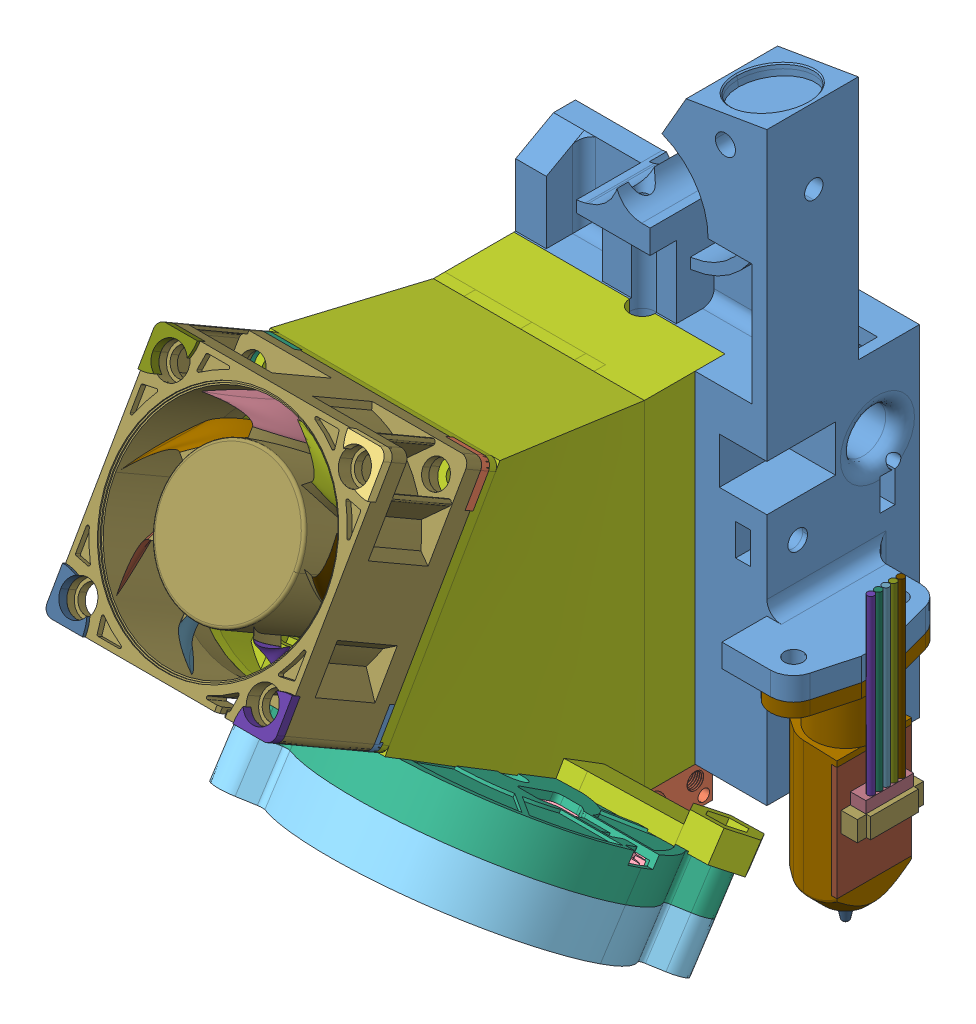
SolidWorks assembly orca-2-cygnus-e3d-extruder+bltouch, configuration Default. Lengths in mm.
Overall size (80.28 120.16 105.46).
52 component instances, 36 part files, 14 mates.
Components (placement in the parent):
- orca2_single_extruder_base-orca2 cyg isolated extruder-1: orca2_single_extruder_base-orca2 cyg isolated extruder [Default] at origin size (77.53 101.68 34.3)
- e3d_v6_175-1: e3d_v6_175 [Default] at (-15.9108 -245.9364 162.3902) x (0 0 1) z (0 1 0) size (28.15 25.09 61.3)
  - Heaterblock.stp-1: Heaterblock.stp [Default] at (45.073 9.7855 4.6892) size (20 16.05 11.6)
  - Heatsink.stp-1: Heatsink.stp [Default] at (11.1849 26.0506 18.2892) x (0.990938 -0.134318 0) z (0 0 1) size (22.3 22.3 42.75)
  - Nozzle 0.4mm.stp-1: Nozzle 0.4mm.stp [Default] at (26.1197 -35.9963 1.6892) x (0.866025 -0.5 0) z (0 0 1) size (8.08 7 12.54)
  - Heatbreak.stp-1: Heatbreak.stp [Default] at (4.469 -23.4963 11.1892) size (7.03 7.04 22.45)
- BLTouch-Smart V3.1-1: BLTouch-Smart V3.1 [BLTouch-Smart V3.1] at (-70.1572 -203.2472 166.8592) x (0 0 -1) z (0 1 0) size (26 15.35 53.8) (hidden)
  - 93245A111-1: 93245A111 [93245A111] at (0 0 -2.4994) size (4.89 4.75 5.01)
  - BL-touch-1: BL-touch [BL-touch] at origin size (26 12.6 36.68)
  - BL-touch-0-1: BL-touch-0 [BL-touch-0] at origin size (2.08 2.08 10)
  - BL-touch-1-1: BL-touch-1 [BL-touch-1] at origin size (12.93 1 19.75)
  - BL-touch-2-1: BL-touch-2 [BL-touch-2] at origin size (11.5 3.5 3.5)
  - BL-touch-3-1: BL-touch-3 [BL-touch-3] at origin size (8.3 2.7 2)
  - BL-touch-4-1: BL-touch-4 [BL-touch-4] at origin size (1.2 1.2 30)
  - BL-touch-5-1: BL-touch-5 [BL-touch-5] at origin size (1.2 1.2 30)
  - BL-touch-6-1: BL-touch-6 [BL-touch-6] at origin size (1.2 1.2 30)
  - BL-touch-7-1: BL-touch-7 [BL-touch-7] at origin size (1.2 1.2 30)
  - BL-touch-8-1: BL-touch-8 [BL-touch-8] at origin size (1.2 1.2 30)
- NF-A4X20 5V PWM-1: NF-A4X20 5V PWM [NF-A4X20 5V PWM] at (-39.4072 -175.8357 223.2475) x (1 0 0) z (0 0.5 0.866025) size (39.9 39.9 21.15)
  - NF-A4X20 5V PWM1-1: NF-A4X20 5V PWM1 [NF-A4X20 5V PWM1] at origin size (6.87 6.87 1.6)
  - NF-A4X20 5V PWM2-1: NF-A4X20 5V PWM2 [NF-A4X20 5V PWM2] at origin size (10.4 13.51 17.16)
  - NF-A4X20 5V PWM3-1: NF-A4X20 5V PWM3 [NF-A4X20 5V PWM3] at origin size (15.27 8.16 17.16)
  - NF-A4X20 5V PWM4-1: NF-A4X20 5V PWM4 [NF-A4X20 5V PWM4] at origin size (11.08 12.64 17.16)
  - NF-A4X20 5V PWM5-1: NF-A4X20 5V PWM5 [NF-A4X20 5V PWM5] at origin size (6.87 6.87 1.6)
  - NF-A4X20 5V PWM6-1: NF-A4X20 5V PWM6 [NF-A4X20 5V PWM6] at origin size (5.87 16.26 17.16)
  - NF-A4X20 5V PWM7-1: NF-A4X20 5V PWM7 [NF-A4X20 5V PWM7] at origin size (39.9 39.9 19.95)
  - NF-A4X20 5V PWM8-1: NF-A4X20 5V PWM8 [NF-A4X20 5V PWM8] at origin size (16.44 4.89 17.16)
  - NF-A4X20 5V PWM9-1: NF-A4X20 5V PWM9 [NF-A4X20 5V PWM9] at origin size (14.54 8.2 17.16)
  - NF-A4X20 5V PWM10-1: NF-A4X20 5V PWM10 [NF-A4X20 5V PWM10] at origin size (6.87 6.87 1.6)
  - NF-A4X20 5V PWM11-1: NF-A4X20 5V PWM11 [NF-A4X20 5V PWM11] at origin size (6.87 6.87 1.6)
  - NF-A4X20 5V PWM12-1: NF-A4X20 5V PWM12 [NF-A4X20 5V PWM12] at origin size (6.87 6.87 1.6)
  - NF-A4X20 5V PWM13-1: NF-A4X20 5V PWM13 [NF-A4X20 5V PWM13] at origin size (6.71 15.85 17.16)
  - NF-A4X20 5V PWM14-1: NF-A4X20 5V PWM14 [NF-A4X20 5V PWM14] at origin size (6.87 6.87 1.6)
  - NF-A4X20 5V PWM15-1: NF-A4X20 5V PWM15 [NF-A4X20 5V PWM15] at origin size (6.87 6.87 1.6)
  - NF-A4X20 5V PWM16-1: NF-A4X20 5V PWM16 [NF-A4X20 5V PWM16] at origin size (6.87 6.87 1.6)
- Radial-Cooling-Fan-5015-DC12V-1: Radial-Cooling-Fan-5015-DC12V [По умолчанию] at (-21.6176 -209.7735 207.5314) x (1 0 0) z (0 -0.547129 -0.837048) size (51.3 15 51.07)
  - turbine-1: turbine [По умолчанию] at (0 3.2 0) x (0.990476 0 -0.137682) z (0.137682 0 0.990476) size (38.96 10.5 38.91)
  - top-3: top [По умолчанию] at (0 15 0) size (51.3 8 51.07)
  - bottom-1: bottom [По умолчанию] at origin size (51.3 8.5 51.07)
- Fan Shroud 2-1: Fan Shroud 2 [Default] at (0 0 178.8592) size (65.59 69.2 66.36)
- BLTouch-Smart V3.1-2: BLTouch-Smart V3.1 [BLTouch-Smart V3.1] at (-4.1238 -203.2472 166.8592) x (0 0 1) z (0 1 0) size (26 15.35 53.8)
  - 93245A111-1: 93245A111 [93245A111] at (0 0 -2.4994) size (4.89 4.75 5.01)
  - BL-touch-1: BL-touch [BL-touch] at origin size (26 12.6 36.68)
  - BL-touch-0-1: BL-touch-0 [BL-touch-0] at origin size (2.08 2.08 10)
  - BL-touch-1-1: BL-touch-1 [BL-touch-1] at origin size (12.93 1 19.75)
  - BL-touch-2-1: BL-touch-2 [BL-touch-2] at origin size (11.5 3.5 3.5)
  - BL-touch-3-1: BL-touch-3 [BL-touch-3] at origin size (8.3 2.7 2)
  - BL-touch-4-1: BL-touch-4 [BL-touch-4] at origin size (1.2 1.2 30)
  - BL-touch-5-1: BL-touch-5 [BL-touch-5] at origin size (1.2 1.2 30)
  - BL-touch-6-1: BL-touch-6 [BL-touch-6] at origin size (1.2 1.2 30)
  - BL-touch-7-1: BL-touch-7 [BL-touch-7] at origin size (1.2 1.2 30)
  - BL-touch-8-1: BL-touch-8 [BL-touch-8] at origin size (1.2 1.2 30)
Mates (geometry in assembly coordinates):
- Concentric1: concentric aligned: circle of orca2_single_extruder_base-orca2 cyg isolated extruder-1; circle of e3d_v6_175-1/Heatsink.stp-1
- Perpendicular1: perpendicular: plane of e3d_v6_175-1 through (-39.4072 -245.9364 162.3902) normal (-1 0 0); plane of orca2_single_extruder_base-orca2 cyg isolated extruder-1 through (0 0 166.8592) normal (0 0 1)
- Distance1: distance = 3 mm aligned: plane of BLTouch-Smart V3.1-1/BL-touch-0-1 through (-70.1572 -243.2472 166.466) normal (0 -1 0); plane of e3d_v6_175-1/Nozzle 0.4mm.stp-1 through (-39.4072 -246.2472 166.8592) normal (0 -1 0)
- Distance4: distance = 25 mm anti-aligned: plane of BLTouch-Smart V3.1-1/BL-touch-1 through (-64.4072 -213.6472 162.8592) normal (1 0 0); plane of e3d_v6_175-1 through (-39.4072 -245.9364 162.3902) normal (-1 0 0)
- Coincident11: coincident aligned: plane of e3d_v6_175-1 through (-15.9108 -245.9364 166.8592) normal (0 0 -1); plane of BLTouch-Smart V3.1-1 through (-70.1572 -203.2472 166.8592) normal (0 0 -1)
- Coincident24: coincident anti-aligned: plane of orca2_single_extruder_base-orca2 cyg isolated extruder-1 through (-39.4072 -188.6472 166.8592) normal (0 1 0); plane of e3d_v6_175-1/Heatsink.stp-1 through (-33.4616 -188.6472 167.6651) normal (0 -1 0)
- Coincident30: coincident anti-aligned: plane of e3d_v6_175-1 through (-39.4072 -245.9364 162.3902) normal (-1 0 0); plane of NF-A4X20 5V PWM-1 through (-39.4072 -175.8357 223.2475) normal (1 0 0)
- InPlace1: in place: plane of ? through (0 0 178.0092) normal (0 0 1); moOrthogonalPlaneRef_w of ? through (0 0 178.0092) normal (0 1 0); plane of ? through (0 0 178.0092) normal (1 0 0); unknown of Fan Shroud 2-1
- Coincident35: coincident aligned: 
- Coincident36: coincident aligned: plane of Fan Shroud 2-1 through (0 0 178.8592) normal (0 1 0)
- Coincident37: coincident anti-aligned: plane of Fan Shroud 2-1 through (0 0 178.8592) normal (1 0 0)
- Concentric2: concentric: circle of orca2_single_extruder_base-orca2 cyg isolated extruder-1; circle of BLTouch-Smart V3.1-2/BL-touch-1
- Concentric3: concentric: circle of orca2_single_extruder_base-orca2 cyg isolated extruder-1; circle of BLTouch-Smart V3.1-2/BL-touch-1
- Coincident33: coincident anti-aligned: plane of orca2_single_extruder_base-orca2 cyg isolated extruder-1 through (-4.1238 -203.2472 175.8592) normal (0 -1 0); plane of BLTouch-Smart V3.1-2/BL-touch-1 through (-4.1238 -203.2472 166.8592) normal (0 1 0)
